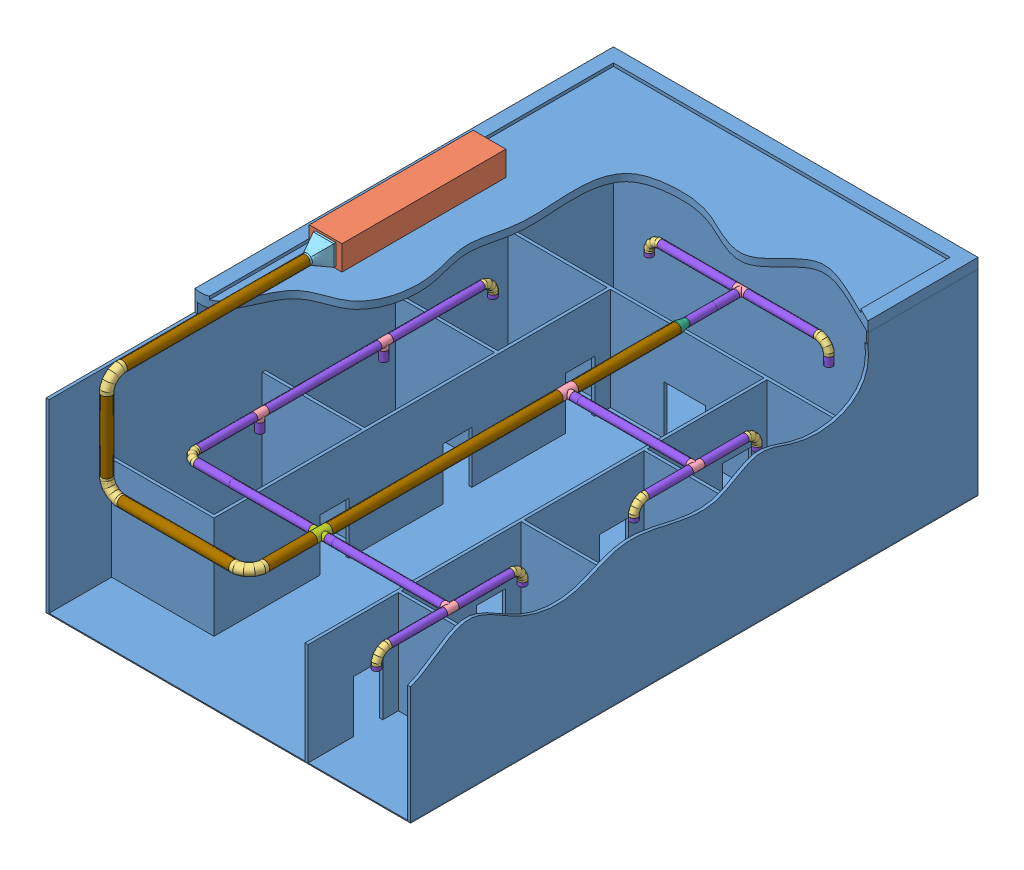
SolidWorks assembly HVAC Round System, configuration Default. Lengths in mm.
Overall size (35600 22247 55402.28).
55 component instances, 9 part files, 4 mates.
Components (placement in the parent):
- Part-1: Part [Default] at origin size (35600 20147 55402.28)
- Part1^HVAC Round System-1: Part1^HVAC Round System [Default] at (0 19747 0) x (1 0 0) z (0 1 0) size (3200 16000 2400) (virtual)
- HVAC Ducting10-HVAC Round System-1: HVAC Ducting10-HVAC Round System [Default] at origin size (28079.33 12943.59 49335.66)
  - hvac round duct 90deg elbow-1: hvac round duct 90deg elbow [Round Duct 90Deg Elbow 0.75DIA x 1.13R] at (12650 9875 -975) x (0 -1 0) z (-1 0 0) size (1510 1510 750)
  - hvac round duct 90deg elbow-3: hvac round duct 90deg elbow [Round Duct 90Deg Elbow 0.75DIA x 1.13R] at (12650 9875 -10725) x (0 -1 0) z (1 0 0) size (1510 1510 750)
  - hvac round duct 90deg elbow-6: hvac round duct 90deg elbow [Round Duct 90Deg Elbow 0.75DIA x 1.13R] at (12650 9875 12150) x (0 -1 0) z (1 0 0) size (1510 1510 750)
  - hvac round duct 90deg elbow-8: hvac round duct 90deg elbow [Round Duct 90Deg Elbow 0.75DIA x 1.13R] at (12650 9875 24150) x (0 -1 0) z (-1 0 0) size (1510 1510 750)
  - hvac round duct tee-1: hvac round duct tee [Round Duct Tee 0.75 x 0.75 x 0.75] at (-13114.7749 11000 -1197.8664) x (0 0 1) z (1 0 0) size (1145 947.5 750)
  - hvac round duct 90deg elbow-13: hvac round duct 90deg elbow [Round Duct 90Deg Elbow 0.75DIA x 1.13R] at (-13114.7749 9875 -10725) x (0 -1 0) z (1 0 0) size (1510 1510 750)
  - hvac round duct 90deg elbow-15: hvac round duct 90deg elbow [Round Duct 90Deg Elbow 0.75DIA x 1.13R] at (-7875 9875 -23000) x (0 -1 0) z (0 0 -1) size (1510 1510 750)
  - hvac round duct tee-5: hvac round duct tee [Round Duct Tee 0.75 x 0.75 x 0.75] at (0 11000 -23000) x (1 0 0) z (0 -1 0) size (1145 947.5 750)
  - hvac round duct tee-7: hvac round duct tee [Round Duct Tee 0.75 x 0.75 x 0.75] at (12650 11000 -5850) x (0 0 -1) z (0 1 0) size (1145 947.5 750)
  - hvac round duct tee-8: hvac round duct tee [Round Duct Tee 0.75 x 0.75 x 0.75] at (12650 11000 18150) x (0 0 -1) z (0 1 0) size (1145 947.5 750)
  - hvac round duct tee-12: hvac round duct tee [Round Duct Tee 0.75 x 0.75 x 0.75] at (-13114.7749 11000 10919.1216) x (0 0 -1) z (-1 0 0) size (1145 947.5 750)
  - hvac round duct 90deg elbow-16: hvac round duct 90deg elbow [Round Duct 90Deg Elbow 0.75DIA x 1.13R] at (7406.5004 9875 -23000) x (0 -1 0) z (0 0 1) size (1510 1510 750)
  - hvac square-round-1: hvac square-round [Square_Round 2.00x2.00 to 1.00 DIA] at (-13899 20946 3700) x (0 0 1) z (-1 0 0) size (2020 2000 2000)
  - hvac round duct 90deg elbow-17: hvac round duct 90deg elbow [Round Duct 90Deg Elbow 1.00DIA x 1.50R] at (-13899 19446 23567.2282) x (0 -1 0) z (-1 0 0) size (2010 2010 1000)
  - hvac round duct 90deg elbow-18: hvac round duct 90deg elbow [Round Duct 90Deg Elbow 1.00DIA x 1.50R] at (-12399 12500 25067.2282) x (1 0 0) z (0 0 -1) size (2010 2010 1000)
  - hvac round duct 90deg elbow-19: hvac round duct 90deg elbow [Round Duct 90Deg Elbow 1.00DIA x 1.50R] at (-1500 11000 23567.2282) x (0 0 -1) z (0 -1 0) size (2010 2010 1000)
  - hvac round reducer-2: hvac round reducer [Round Duct Reducer 1.00 x 0.75] at (0 11000 -16618.6901) x (0 0 -1) z (1 0 0) size (1020 1000 1000)
  - hvac round duct cross-1: hvac round duct cross [Round Duct Cross 1.00 x 1.00 x 0.75 x 0.75] at (0 11000 18150) x (0 0 1) z (0 1 0) size (1520 1520 1000)
  - hvac round duct tee-13: hvac round duct tee [Round Duct Tee 1.00 x 1.00 x 0.75] at (0 11000 -5850) x (0 0 1) z (0 1 0) size (1520 1260 1000)
  - hvac round duct 90deg elbow-20: hvac round duct 90deg elbow [Round Duct 90Deg Elbow 0.75DIA x 1.13R] at (-11989.7749 11000 17025) x (0 0 -1) z (0 1 0) size (1510 1510 750)
  - RoundDuct075mDIA2mmThick^HVAC Ducting10-HVAC Round System-1: RoundDuct075mDIA2mmThick^HVAC Ducting10-HVAC Round System [Round Duct 0.75m DIA,2mm Thick, 2] at (12650 11000 -5287.5) x (0.707107 0.707107 0) z (0 0 1) size (750 750 4312.5) (virtual)
  - RoundDuct075mDIA2mmThick^HVAC Ducting10-HVAC Round System-2: RoundDuct075mDIA2mmThick^HVAC Ducting10-HVAC Round System [Round Duct 0.75m DIA,2mm Thick, 3] at (12650 9875 150) x (0.707107 0 0.707107) z (0 -1 0) size (750 750 375) (virtual)
  - RoundDuct075mDIA2mmThick^HVAC Ducting10-HVAC Round System-3: RoundDuct075mDIA2mmThick^HVAC Ducting10-HVAC Round System [Round Duct 0.75m DIA,2mm Thick, 2] at (12650 11000 -6412.5) x (0.707107 0.707107 0) z (0 0 -1) size (750 750 4312.5) (virtual)
  - RoundDuct075mDIA2mmThick^HVAC Ducting10-HVAC Round System-4: RoundDuct075mDIA2mmThick^HVAC Ducting10-HVAC Round System [Round Duct 0.75m DIA,2mm Thick, 3] at (12650 9875 -11850) x (0.707107 0 0.707107) z (0 -1 0) size (750 750 375) (virtual)
  - RoundDuct075mDIA2mmThick^HVAC Ducting10-HVAC Round System-5: RoundDuct075mDIA2mmThick^HVAC Ducting10-HVAC Round System [Round Duct 0.75m DIA,2mm Thick] at (12650 11000 18712.5) x (0.707107 0.707107 0) z (0 0 1) size (750 750 5437.5) (virtual)
  - RoundDuct075mDIA2mmThick^HVAC Ducting10-HVAC Round System-6: RoundDuct075mDIA2mmThick^HVAC Ducting10-HVAC Round System [Round Duct 0.75m DIA,2mm Thick] at (12650 11000 17587.5) x (0.707107 0.707107 0) z (0 0 -1) size (750 750 5437.5) (virtual)
  - RoundDuct075mDIA2mmThick^HVAC Ducting10-HVAC Round System-9: RoundDuct075mDIA2mmThick^HVAC Ducting10-HVAC Round System [Round Duct 0.75m DIA,2mm Thick, 3] at (12650 9875 11025) x (0.707107 0 0.707107) z (0 -1 0) size (750 750 375) (virtual)
  - RoundDuct075mDIA2mmThick^HVAC Ducting10-HVAC Round System-12: RoundDuct075mDIA2mmThick^HVAC Ducting10-HVAC Round System [Round Duct 0.75m DIA,2mm Thick, 3] at (12650 9875 25275) x (0.707107 0 0.707107) z (0 -1 0) size (750 750 375) (virtual)
  - RoundDuct075mDIA2mmThick^HVAC Ducting10-HVAC Round System-14: RoundDuct075mDIA2mmThick^HVAC Ducting10-HVAC Round System [Round Duct 0.75m DIA,2mm Thick, 4] at (-13114.7749 11000 -1760.3664) x (0.707107 0.707107 0) z (0 0 -1) size (750 750 8964.63) (virtual)
  - RoundDuct075mDIA2mmThick^HVAC Ducting10-HVAC Round System-15: RoundDuct075mDIA2mmThick^HVAC Ducting10-HVAC Round System [Round Duct 0.75m DIA,2mm Thick, 5] at (-13114.7749 10437.5 -1197.8664) x (0.707107 0 0.707107) z (0 -1 0) size (750 750 937.5) (virtual)
  - RoundDuct075mDIA2mmThick^HVAC Ducting10-HVAC Round System-22: RoundDuct075mDIA2mmThick^HVAC Ducting10-HVAC Round System [Round Duct 0.75m DIA,2mm Thick, 3] at (-13114.7749 9875 -11850) x (0.707107 0 0.707107) z (0 -1 0) size (750 750 375) (virtual)
  - RoundDuct075mDIA2mmThick^HVAC Ducting10-HVAC Round System-27: RoundDuct075mDIA2mmThick^HVAC Ducting10-HVAC Round System [Round Duct 0.75m DIA,2mm Thick, 8] at (-562.5 11000 -23000) x (0 0.707107 0.707107) z (-1 0 0) size (750 750 7312.5) (virtual)
  - RoundDuct075mDIA2mmThick^HVAC Ducting10-HVAC Round System-29: RoundDuct075mDIA2mmThick^HVAC Ducting10-HVAC Round System [Round Duct 0.75m DIA,2mm Thick, 3] at (-9000 9875 -23000) x (0.707107 0 0.707107) z (0 -1 0) size (750 750 375) (virtual)
  - RoundDuct075mDIA2mmThick^HVAC Ducting10-HVAC Round System-34: RoundDuct075mDIA2mmThick^HVAC Ducting10-HVAC Round System [Round Duct 0.75m DIA,2mm Thick, 1] at (-13114.7749 11000 -635.3664) x (0.707107 0.707107 0) z (0 0 1) size (750 750 10991.99) (virtual)
  - RoundDuct075mDIA2mmThick^HVAC Ducting10-HVAC Round System-38: RoundDuct075mDIA2mmThick^HVAC Ducting10-HVAC Round System [Round Duct 0.75m DIA,2mm Thick, 11] at (-13114.7749 11000 11481.6216) x (0.707107 0.707107 0) z (0 0 1) size (750 750 5543.38) (virtual)
  - RoundDuct075mDIA2mmThick^HVAC Ducting10-HVAC Round System-40: RoundDuct075mDIA2mmThick^HVAC Ducting10-HVAC Round System [Round Duct 0.75m DIA,2mm Thick, 5] at (-13114.7749 10437.5 10919.1216) x (0.707107 0 0.707107) z (0 -1 0) size (750 750 937.5) (virtual)
  - RoundDuct075mDIA2mmThick^HVAC Ducting10-HVAC Round System-41: RoundDuct075mDIA2mmThick^HVAC Ducting10-HVAC Round System [Round Duct 0.75m DIA,2mm Thick, 12] at (0 11000 -22437.5) x (0.707107 0.707107 0) z (0 0 1) size (750 750 2187.58) (virtual)
  - RoundDuct075mDIA2mmThick^HVAC Ducting10-HVAC Round System-45: RoundDuct075mDIA2mmThick^HVAC Ducting10-HVAC Round System [Round Duct 0.75m DIA,2mm Thick, 9] at (562.5 11000 -23000) x (0 0.707107 0.707107) z (1 0 0) size (750 750 6844) (virtual)
  - RoundDuct075mDIA2mmThick^HVAC Ducting10-HVAC Round System-46: RoundDuct075mDIA2mmThick^HVAC Ducting10-HVAC Round System [Round Duct 0.75m DIA,2mm Thick, 10] at (8531.5004 9875 -23000) x (0.707107 0 0.707107) z (0 -1 0) size (750 750 872.59) (virtual)
  - RoundDuct100mDIA2mmThick^HVAC Ducting10-HVAC Round System-1: RoundDuct100mDIA2mmThick^HVAC Ducting10-HVAC Round System [Round Duct 1.00m DIA,2mm Thick] at (-13899 20946 5700) x (0.707107 0.707107 0) z (0 0 1) size (1000 1000 17867.23) (virtual)
  - RoundDuct100mDIA2mmThick^HVAC Ducting10-HVAC Round System-2: RoundDuct100mDIA2mmThick^HVAC Ducting10-HVAC Round System [Round Duct 1.00m DIA,2mm Thick, 1] at (-13899 19446 25067.2282) x (0.707107 0 0.707107) z (0 -1 0) size (1000 1000 6946) (virtual)
  - RoundDuct100mDIA2mmThick^HVAC Ducting10-HVAC Round System-3: RoundDuct100mDIA2mmThick^HVAC Ducting10-HVAC Round System [Round Duct 1.00m DIA,2mm Thick, 2] at (-12399 11000 25067.2282) x (0 0.707107 0.707107) z (1 0 0) size (1000 1000 10899) (virtual)
  - RoundDuct100mDIA2mmThick^HVAC Ducting10-HVAC Round System-4: RoundDuct100mDIA2mmThick^HVAC Ducting10-HVAC Round System [Round Duct 1.00m DIA,2mm Thick, 4] at (0 11000 23567.2282) x (0.707107 0.707107 0) z (0 0 -1) size (1000 1000 4667.23) (virtual)
  - RoundDuct075mDIA2mmThick^HVAC Ducting10-HVAC Round System-47: RoundDuct075mDIA2mmThick^HVAC Ducting10-HVAC Round System [Round Duct 0.75m DIA,2mm Thick, 13] at (0 11000 -17618.6901) x (0.707107 0.707107 0) z (0 0 -1) size (750 750 2631.23) (virtual)
  - RoundDuct100mDIA2mmThick^HVAC Ducting10-HVAC Round System-5: RoundDuct100mDIA2mmThick^HVAC Ducting10-HVAC Round System [Round Duct 1.00m DIA,2mm Thick, 5] at (0 11000 17400) x (0.707107 0.707107 0) z (0 0 -1) size (1000 1000 22500) (virtual)
  - RoundDuct075mDIA2mmThick^HVAC Ducting10-HVAC Round System-48: RoundDuct075mDIA2mmThick^HVAC Ducting10-HVAC Round System [Round Duct 0.75m DIA,2mm Thick, 14] at (-750 11000 18150) x (0 0.707107 0.707107) z (-1 0 0) size (750 750 7770.76) (virtual)
  - RoundDuct075mDIA2mmThick^HVAC Ducting10-HVAC Round System-49: RoundDuct075mDIA2mmThick^HVAC Ducting10-HVAC Round System [Round Duct 0.75m DIA,2mm Thick, 7] at (750 11000 18150) x (0 0.707107 0.707107) z (1 0 0) size (750 750 750) (virtual)
  - RoundDuct075mDIA2mmThick^HVAC Ducting10-HVAC Round System-50: RoundDuct075mDIA2mmThick^HVAC Ducting10-HVAC Round System [Round Duct 0.75m DIA,2mm Thick, 15] at (12087.5 11000 18150) x (0 0.707107 0.707107) z (-1 0 0) size (750 750 10587.5) (virtual)
  - RoundDuct075mDIA2mmThick^HVAC Ducting10-HVAC Round System-51: RoundDuct075mDIA2mmThick^HVAC Ducting10-HVAC Round System [Round Duct 0.75m DIA,2mm Thick, 16] at (-11989.7749 11000 18150) x (0 0.707107 0.707107) z (1 0 0) size (750 750 3469.02) (virtual)
  - RoundDuct075mDIA2mmThick^HVAC Ducting10-HVAC Round System-52: RoundDuct075mDIA2mmThick^HVAC Ducting10-HVAC Round System [Round Duct 0.75m DIA,2mm Thick, 15] at (12087.5 11000 -5850) x (0 0.707107 0.707107) z (-1 0 0) size (750 750 10587.5) (virtual)
  - RoundDuct100mDIA2mmThick^HVAC Ducting10-HVAC Round System-6: RoundDuct100mDIA2mmThick^HVAC Ducting10-HVAC Round System [Round Duct 1.00m DIA,2mm Thick, 6] at (0 11000 -6600) x (0.707107 0.707107 0) z (0 0 -1) size (1000 1000 10018.69) (virtual)
  - RoundDuct075mDIA2mmThick^HVAC Ducting10-HVAC Round System-53: RoundDuct075mDIA2mmThick^HVAC Ducting10-HVAC Round System [Round Duct 0.75m DIA,2mm Thick, 7] at (750 11000 -5850) x (0 0.707107 0.707107) z (1 0 0) size (750 750 750) (virtual)
Mates (geometry in assembly coordinates):
- InPlace1: in place: plane of Part-1 through (0 19747 0) normal (0 1 0); plane of Part1^HVAC Round System-1 through (0 19747 0) normal (0 1 0); moOrthogonalPlaneRef_w of Part-1 through (0 19747 0) normal (0 1 0); plane of Part1^HVAC Round System-1 through (0 19747 0) normal (0 0 -1); plane of Part-1 through (0 19747 0) normal (0 1 0); plane of Part1^HVAC Round System-1 through (0 19747 0) normal (1 0 0); plane of Part-1 through (0 19747 0) normal (0 1 0); unknown of Part1^HVAC Round System-1
- Coincident1: coincident aligned: plane of ?; plane of ?
- Coincident2: coincident aligned: moOrthogonalPlaneRef_w of Part-1 through (0 19747 0) normal (0 0 -1); plane of Part1^Assem2-1 through (0 19747 0) normal (0 0 -1)
- Coincident3: coincident anti-aligned: moOrthogonalPlaneRef_w of Part-1 through (0 19747 0) normal (-1 0 0); plane of Part1^Assem2-1 through (0 19747 0) normal (1 0 0)
